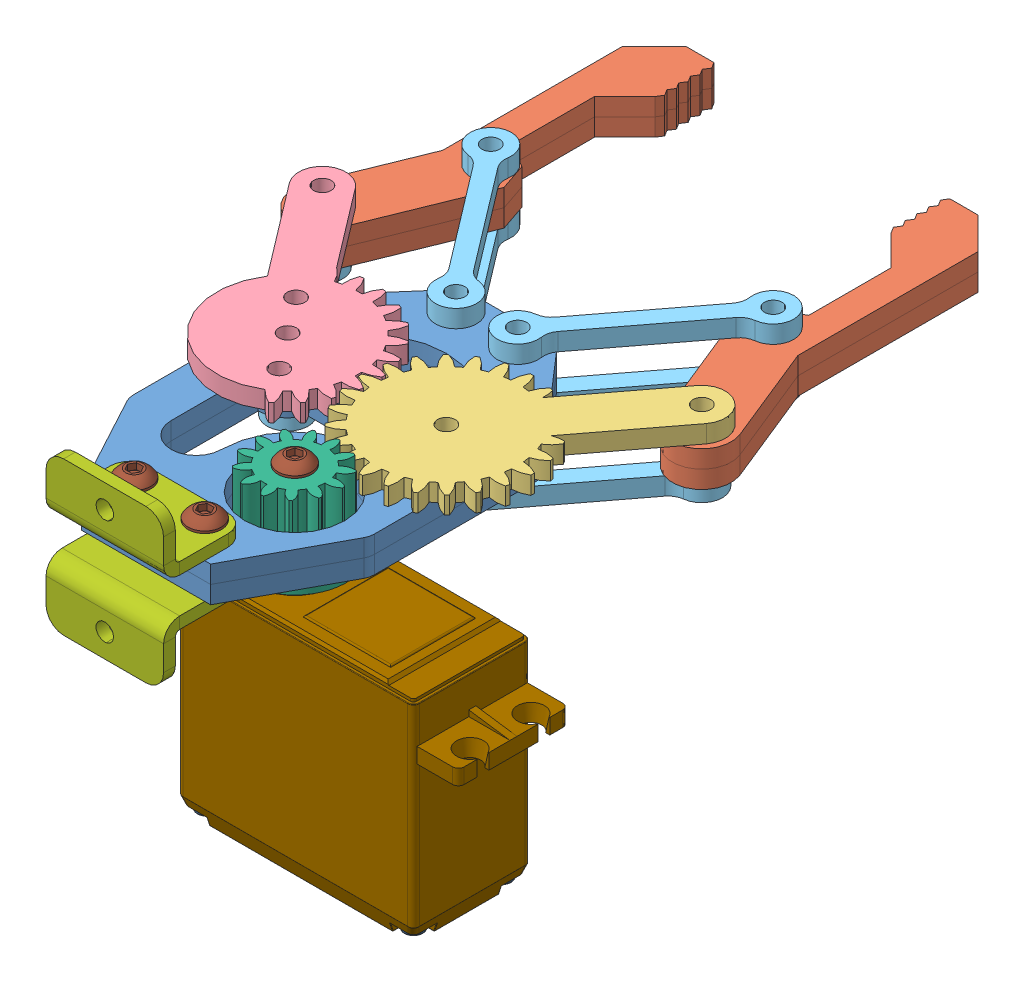
SolidWorks assembly Assemblage_pince_moteur, configuration Défaut. Lengths in mm.
Overall size (98.86 57.4 126.45).
29 component instances, 12 part files, 42 mates.
Components (placement in the parent):
- Arm 03-1: Arm 03 [Default] at (35.5703 37.2102 28.0072) size (41 3 62)
- Arm 07-1: Arm 07 [Default] at (7.4269 37.2102 -6.8629) x (0 1 0) z (-0.375 0 0.927025) size (3 21.49 60.01)
- Arm 04-1: Arm 04 [Default] at (49.9311 40.2102 27.2547) x (0.605431 0 -0.795898) z (0.795898 0 0.605431) size (49.54 3 29.07)
- Arm 05-1: Arm 05 [Default] at (22.1541 40.2102 28.0392) x (0.254768 0 0.967002) z (-0.967002 0 0.254768) size (46.27 3 30.4)
- Arm 06-1: Arm 06 [Default] at (20.9361 40.2102 -4.7238) x (-0.605431 0 -0.795898) z (0.795898 0 -0.605431) size (38 3 7)
- Arm 06-2: Arm 06 [Default] at (50.2044 40.2102 -4.7238) x (0.605431 0 -0.795898) z (0.795898 0 0.605431) size (38 3 7)
- Arm 07-6: Arm 07 [Default] at (63.7136 37.2102 -6.8629) x (0 -1 0) z (0.375 0 0.927025) size (3 21.49 60.01)
- Arm 03-5: Arm 03 [Default] at (35.5703 34.2102 28.0072) size (41 3 62)
- Arm 07-13: Arm 07 [Default] at (7.4269 34.2102 -6.8629) x (0 1 0) z (-0.375 0 0.927025) size (3 21.49 60.01)
- Arm 07-14: Arm 07 [Default] at (63.7136 34.2102 -6.8629) x (0 -1 0) z (0.375 0 0.927025) size (3 21.49 60.01)
- Arm 06-8: Arm 06 [Default] at (20.9361 31.2102 -4.7238) x (-0.605431 0 -0.795898) z (0.795898 0 -0.605431) size (38 3 7)
- Arm 06-9: Arm 06 [Default] at (50.2044 31.2102 -4.7238) x (0.605431 0 -0.795898) z (0.795898 0 0.605431) size (38 3 7)
- Arm 06-10: Arm 06 [Default] at (12.6861 31.2102 15.6707) x (-0.605431 0 -0.795898) z (-0.795898 0 0.605431) size (38 3 7)
- Arm 06-12: Arm 06 [Default] at (58.4544 31.2102 15.6707) x (0.605431 0 -0.795898) z (-0.795898 0 -0.605431) size (38 3 7)
- shaft+engrenage-1: shaft+engrenage [Défaut] at (28.5882 32.9821 57.8541) x (0 1 0) z (0.887771 0 -0.460286) size (13 17.5 17.5)
- Arm 02-1: Arm 02 [Default] at (35.5703 40.7102 70.6069) x (-1 0 0) z (0 0 -1) size (20 10 14)
- Arm 02-3: Arm 02 [Default] at (35.5703 30.7102 70.6069) x (1 0 0) z (0 0 -1) size (20 10 14)
- Standard Servo Assembly-1: Standard Servo Assembly [Default] at (-192.5139 153.1526 -239.4266) x (0.00041 0 -1) z (1 0 0.00041) size (20.02 42.4 54.21)
  - Servo Output Shaft-1: Servo Output Shaft [Default] at (-287.1544 -128.4424 235.7321) size (6 9 6)
  - Standard Servo (1501MG)-2: Standard Servo (1501MG) [Default] at (-287.1503 -143.8924 245.8321) x (1 0 -0.00041) z (0.00041 0 1) size (20 38.4 54.2)
  - pan head cross recess screw_iso-1: pan head cross recess screw_iso [ISO 7045 - M1.6 x 16 - Z --- 16C] at (-294.6431 -161.6424 263.4352) x (0 1 0) z (0.348576 0 0.937281) size (17.27 3.2 3.2)
  - pan head cross recess screw_iso-2: pan head cross recess screw_iso [ISO 7045 - M1.6 x 16 - Z --- 16C] at (-294.6575 -161.6424 228.2352) x (0 1 0) z (0 0 1) size (17.27 3.2 3.2)
  - pan head cross recess screw_iso-3: pan head cross recess screw_iso [ISO 7045 - M1.6 x 16 - Z --- 16C] at (-279.6575 -161.6424 228.229) x (0 1 0) z (0 0 1) size (17.27 3.2 3.2)
  - pan head cross recess screw_iso-4: pan head cross recess screw_iso [ISO 7045 - M1.6 x 16 - Z --- 16C] at (-279.6431 -161.6424 263.429) x (0 1 0) z (0 0 1) size (17.27 3.2 3.2)
- socket button head screw_iso-6: socket button head screw_iso [ISO 7380 - M3 x 12 - 12N] at (43.1004 44.3602 47.8246) x (0 -1 0) z (-0.257251 0 -0.966345) size (13.65 5.7 5.7)
- socket button head screw_iso-11: socket button head screw_iso [ISO 7380 - M3 x 12 - 12N] at (29.5703 42.3602 61.6069) x (0 -1 0) z (0 0 1) size (13.65 5.7 5.7)
- socket button head screw_iso-12: socket button head screw_iso [ISO 7380 - M3 x 12 - 12N] at (41.5703 42.3602 61.6069) x (0 -1 0) z (0 0 1) size (13.65 5.7 5.7)
- hex thin nut chamfered gradeab_iso-2: hex thin nut chamfered gradeab_iso [ISO - 4035 - M1.6 - N] at (41.5703 30.4445 61.6069) x (1 0 0) z (0 1 0) size (3.2 3.7 1)
- hex thin nut chamfered gradeab_iso-3: hex thin nut chamfered gradeab_iso [ISO - 4035 - M1.6 - N] at (29.5703 30.5707 61.6069) x (1 0 0) z (0 1 0) size (3.2 3.7 1)
Mates (geometry in assembly coordinates):
- Coaxiale1: concentric aligned: cylinder of Arm 03-1 through (49.0703 38.7102 28.0072) axis (0 -1 0) radius 1.5; cylinder of Arm 04-1 through (49.0703 41.7102 28.0072) axis (0 -1 0) radius 1.5
- Coïncidente1: coincident anti-aligned: plane of Arm 03-1 through (35.5703 38.7102 28.0072) normal (0 1 0); plane of Arm 04-1 through (58.4022 38.7102 19.4138) normal (0 -1 0)
- Coaxiale2: concentric aligned: cylinder of Arm 03-1 through (22.0703 38.7102 28.0072) axis (0 -1 0) radius 1.5; cylinder of Arm 05-1 through (22.0703 41.7102 28.0072) axis (0 -1 0) radius 1.5
- Coïncidente2: coincident anti-aligned: plane of Arm 03-1 through (35.5703 38.7102 28.0072) normal (0 1 0); plane of Arm 05-1 through (22.0703 38.7102 28.0072) normal (0 -1 0)
- Coaxiale3: concentric aligned: cylinder of Arm 03-1 through (30.3203 38.7102 7.6126) axis (0 -1 0) radius 1.5; cylinder of Arm 06-1 through (30.3203 41.7102 7.6126) axis (0 -1 0) radius 1.5
- Coïncidente3: coincident anti-aligned: plane of Arm 03-1 through (35.5703 38.7102 28.0072) normal (0 1 0); plane of Arm 06-1 through (29.0341 38.7102 -7.8339) normal (0 -1 0)
- Coaxiale4: concentric aligned: cylinder of Arm 07-1 through (19.4979 38.7102 -2.8859) axis (0 -1 0) radius 1.5; cylinder of Arm 05-1 through (19.4979 41.7102 -2.8859) axis (0 -1 0) radius 1.5
- Coïncidente4: coincident anti-aligned: plane of Arm 07-1 through (23.6229 38.7102 -13.0832) normal (0 1 0); plane of Arm 05-1 through (22.0703 38.7102 28.0072) normal (0 -1 0)
- Coaxiale5: concentric aligned: cylinder of Arm 07-1 through (27.7479 38.7102 -23.2805) axis (0 -1 0) radius 1.5; cylinder of Arm 06-1 through (27.7479 41.7102 -23.2805) axis (0 -1 0) radius 1.5
- Coaxiale6: concentric aligned: cylinder of Arm 03-1 through (40.8203 38.7102 7.6126) axis (0 -1 0) radius 1.5; cylinder of Arm 06-2 through (40.8203 41.7102 7.6126) axis (0 -1 0) radius 1.5
- Coïncidente5: coincident anti-aligned: plane of Arm 03-1 through (35.5703 38.7102 28.0072) normal (0 1 0); plane of Arm 06-2 through (42.1064 38.7102 -7.8339) normal (0 -1 0)
- Coaxiale7: concentric anti-aligned: cylinder of Arm 04-1 through (51.6426 41.7102 -2.8859) axis (0 -1 0) radius 1.5; cylinder of Arm 07-6 through (51.6426 35.7102 -2.8859) axis (0 1 0) radius 1.5
- Coïncidente6: coincident anti-aligned: plane of Arm 04-1 through (58.4022 38.7102 19.4138) normal (0 -1 0); plane of Arm 07-6 through (47.5176 38.7102 -13.0832) normal (0 1 0)
- Coaxiale8: concentric anti-aligned: cylinder of Arm 06-2 through (43.3926 41.7102 -23.2805) axis (0 -1 0) radius 1.5; cylinder of Arm 07-6 through (43.3926 35.7102 -23.2805) axis (0 1 0) radius 1.5
- Coaxiale9: concentric anti-aligned: cylinder of Arm 03-5 through (22.0703 35.7102 28.0072) axis (0 -1 0) radius 1.5; cylinder of Arm 06-10 through (22.0703 29.7102 28.0072) axis (0 1 0) radius 1.5
- Coïncidente7: coincident anti-aligned: plane of Arm 03-5 through (35.5703 32.7102 28.0072) normal (0 -1 0); plane of Arm 06-10 through (20.7841 32.7102 12.5606) normal (0 1 0)
- Coaxiale10: concentric anti-aligned: cylinder of Arm 07-13 through (19.4979 35.7102 -2.8859) axis (0 -1 0) radius 1.5; cylinder of Arm 06-10 through (19.4979 29.7102 -2.8859) axis (0 1 0) radius 1.5
- Coaxiale11: concentric anti-aligned: cylinder of Arm 03-5 through (49.0703 35.7102 28.0072) axis (0 -1 0) radius 1.5; cylinder of Arm 06-12 through (49.0703 29.7102 28.0072) axis (0 1 0) radius 1.5
- Coïncidente8: coincident anti-aligned: plane of Arm 03-5 through (35.5703 32.7102 28.0072) normal (0 -1 0); plane of Arm 06-12 through (50.3564 32.7102 12.5606) normal (0 1 0)
- Coaxiale12: concentric aligned: cylinder of Arm 07-14 through (51.6426 32.7102 -2.8859) axis (0 1 0) radius 1.5; cylinder of Arm 06-12 through (51.6426 29.7102 -2.8859) axis (0 1 0) radius 1.5
- Coaxiale13: concentric anti-aligned: cylinder of Arm 03-1 through (29.5703 38.7102 61.6069) axis (0 -1 0) radius 1.5; cylinder of Arm 02-1 through (29.5703 30.7102 61.6069) axis (0 1 0) radius 1.5
- Coaxiale14: concentric anti-aligned: cylinder of Arm 03-1 through (41.5703 38.7102 61.6069) axis (0 -1 0) radius 1.5; cylinder of Arm 02-1 through (41.5703 30.7102 61.6069) axis (0 1 0) radius 1.5
- Coïncidente9: coincident anti-aligned: plane of Arm 03-1 through (35.5703 38.7102 28.0072) normal (0 1 0); plane of Arm 02-1 through (25.5703 38.7102 70.6069) normal (0 -1 0)
- Coïncidente10: coincident anti-aligned: plane of Arm 03-5 through (35.5703 32.7102 28.0072) normal (0 -1 0); plane of shaft+engrenage-1 through (43.1004 32.7102 47.8246) normal (0 1 0)
- Coaxiale17: concentric anti-aligned: cylinder of Arm 03-5 through (43.1004 35.7102 47.8246) axis (0 -1 0) radius 8.5; cylinder of shaft+engrenage-1 through (43.1004 29.7102 47.8246) axis (0 1 0) radius 8.75
- Coïncidente12: coincident anti-aligned: plane of Arm 03-5 through (35.5703 32.7102 28.0072) normal (0 -1 0); plane of Arm 02-3 through (45.5703 32.7102 70.6069) normal (0 1 0)
- Coaxiale20: concentric aligned: cylinder of Arm 03-5 through (41.5703 35.7102 61.6069) axis (0 -1 0) radius 1.5; cylinder of Arm 02-3 through (41.5703 40.7102 61.6069) axis (0 -1 0) radius 1.5
- Coaxiale21: concentric aligned: cylinder of Arm 03-5 through (29.5703 35.7102 61.6069) axis (0 -1 0) radius 1.5; cylinder of Arm 02-3 through (29.5703 40.7102 61.6069) axis (0 -1 0) radius 1.5
- Parallèle1: parallel anti-aligned: plane of Arm 02-1 through (25.5703 48.7102 72.6069) normal (0 0 1); plane of Standard Servo Assembly-1/Standard Servo (1501MG)-2 through (33.1004 27.2102 37.8246) normal (0 0 -1)
- Coaxiale22: concentric anti-aligned: circle of Arm 03-1; cylinder of Standard Servo Assembly-1/Standard Servo (1501MG)-2 through (43.1004 29.7102 47.8246) axis (0 -1 0) radius 5.5
- Coïncidente13: coincident anti-aligned: plane of shaft+engrenage-1 through (43.1004 29.7102 47.8246) normal (0 -1 0); plane of Standard Servo Assembly-1/Servo Output Shaft-1 through (43.1017 29.7102 44.8246) normal (0 1 0)
- AngleLimite1: limit planar angle = 2.491285 rad anti-aligned: plane of Arm 05-1 through (11.9775 41.7102 21.3461) normal (-0.795898 0 0.605431); plane of Arm 03-1 through (15.0703 38.7102 18.0072) normal (-1 0 0)
- Contr.Engrenages1: gear = 1 : 1 mm: cylinder of Arm 04-1 through (49.0703 41.7102 28.0072) axis (0 -1 0) radius 12.0927; cylinder of Arm 05-1 through (22.0703 41.7102 28.0072) axis (0 -1 0) radius 12.0927
- Contr.Engrenages2: gear = 13 : 24 mm: cylinder of Arm 04-1 through (49.0703 41.7102 28.0072) axis (0 -1 0) radius 12.0927; cylinder of shaft+engrenage-1 through (43.1004 42.7102 47.8246) axis (0 -1 0) radius 5.249
- Coaxiale26: concentric anti-aligned: cylinder of shaft+engrenage-1 through (43.1004 82.7103 47.8246) axis (0 -1 0) radius 0.4; cylinder of socket button head screw_iso-6 through (43.1004 44.3602 47.8246) axis (0 1 0) radius 2.85
- Coïncidente17: coincident anti-aligned: plane of shaft+engrenage-1 through (43.1004 42.7102 47.8246) normal (0 1 0); plane of socket button head screw_iso-6 through (41.6509 42.7102 48.2104) normal (0 -1 0)
- Coaxiale29: concentric aligned: cylinder of Arm 02-1 through (29.5703 30.7102 61.6069) axis (0 1 0) radius 1.5; cylinder of socket button head screw_iso-11 through (29.5703 42.3602 61.6069) axis (0 1 0) radius 2.85
- Coïncidente20: coincident anti-aligned: plane of Arm 02-1 through (25.5703 40.7102 70.6069) normal (0 1 0); plane of socket button head screw_iso-11 through (31.0703 40.7102 61.6069) normal (0 -1 0)
- Coaxiale30: concentric aligned: cylinder of Arm 02-1 through (41.5703 30.7102 61.6069) axis (0 1 0) radius 1.5; cylinder of socket button head screw_iso-12 through (41.5703 42.3602 61.6069) axis (0 1 0) radius 2.85
- Coïncidente21: coincident anti-aligned: plane of Arm 02-1 through (25.5703 40.7102 70.6069) normal (0 1 0); plane of socket button head screw_iso-12 through (43.0703 40.7102 61.6069) normal (0 -1 0)
- Coaxiale31: concentric aligned: cylinder of socket button head screw_iso-12 through (41.5703 42.3602 61.6069) axis (0 1 0) radius 1.5; cylinder of hex thin nut chamfered gradeab_iso-2 through (41.5703 5.407 61.6069) axis (0 1 0) radius 0.8
- Coaxiale32: concentric aligned: cylinder of socket button head screw_iso-11 through (29.5703 42.3602 61.6069) axis (0 1 0) radius 1.5; cylinder of hex thin nut chamfered gradeab_iso-3 through (29.5703 5.5332 61.6069) axis (0 1 0) radius 0.8
